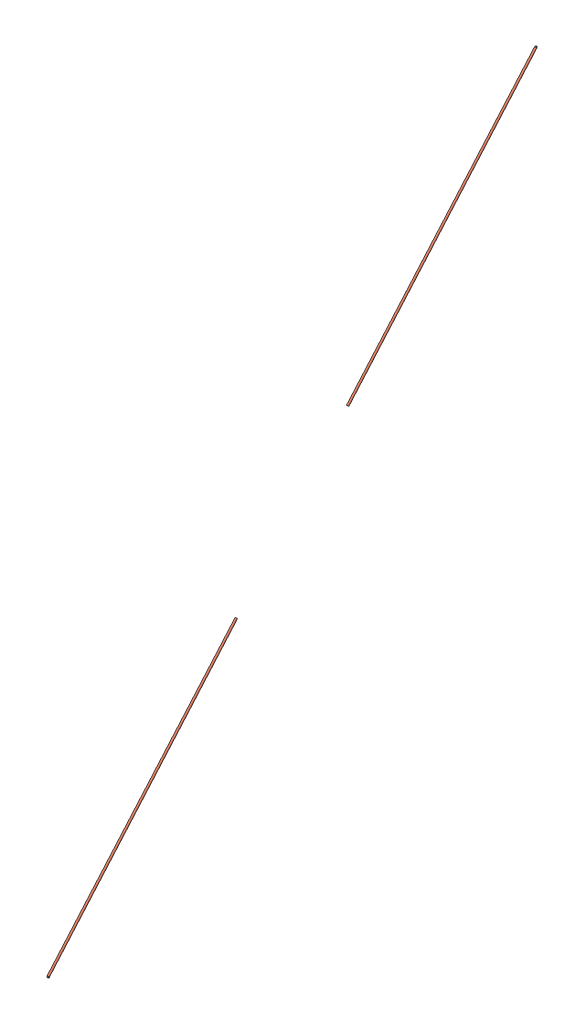
SolidWorks assembly 装配体1, configuration 默认. Lengths in mm.
Overall size (21.76 571.67 533.19).
4 component instances, 2 part files, 3 mates.
Components (placement in the parent):
- 球铰圆-1: 球铰圆 [默认] at (-25.4397 -26.2446 0) size (2 0.1 2)
- 绳-1: 绳 [默认] at (-27.9106 47.58 -68.1665) x (-0.987538 0.088163 0.130372) z (0.155432 0.676392 0.719955) size (2 301 2)
- 绳-3: 绳 [默认] at (-42.1795 469.86 -461.8143) x (-0.47975 -0.606899 -0.633652) z (0.877058 -0.311372 -0.365811) size (2 301 2)
- 球铰圆-3: 球铰圆 [默认] at (-44.1744 542.9137 -530.4892) x (0.725347 0.237848 0.645987) z (0.107234 -0.965998 0.235265) size (2 0.1 2)
Mates (geometry in assembly coordinates):
- 重合1: coincident: circle of 球铰圆-1; sphere of 绳-1
- 同心2: concentric anti-aligned: cylinder of 绳-1 through (-25.4397 -25.5446 0) axis (-0.024709 0.731247 -0.681665) radius 1; cylinder of 绳-3 through (-44.6504 542.9846 -529.9808) axis (0.024709 -0.731247 0.681665) radius 1
- 重合3: coincident: sphere of 绳-3; circle of 球铰圆-3
